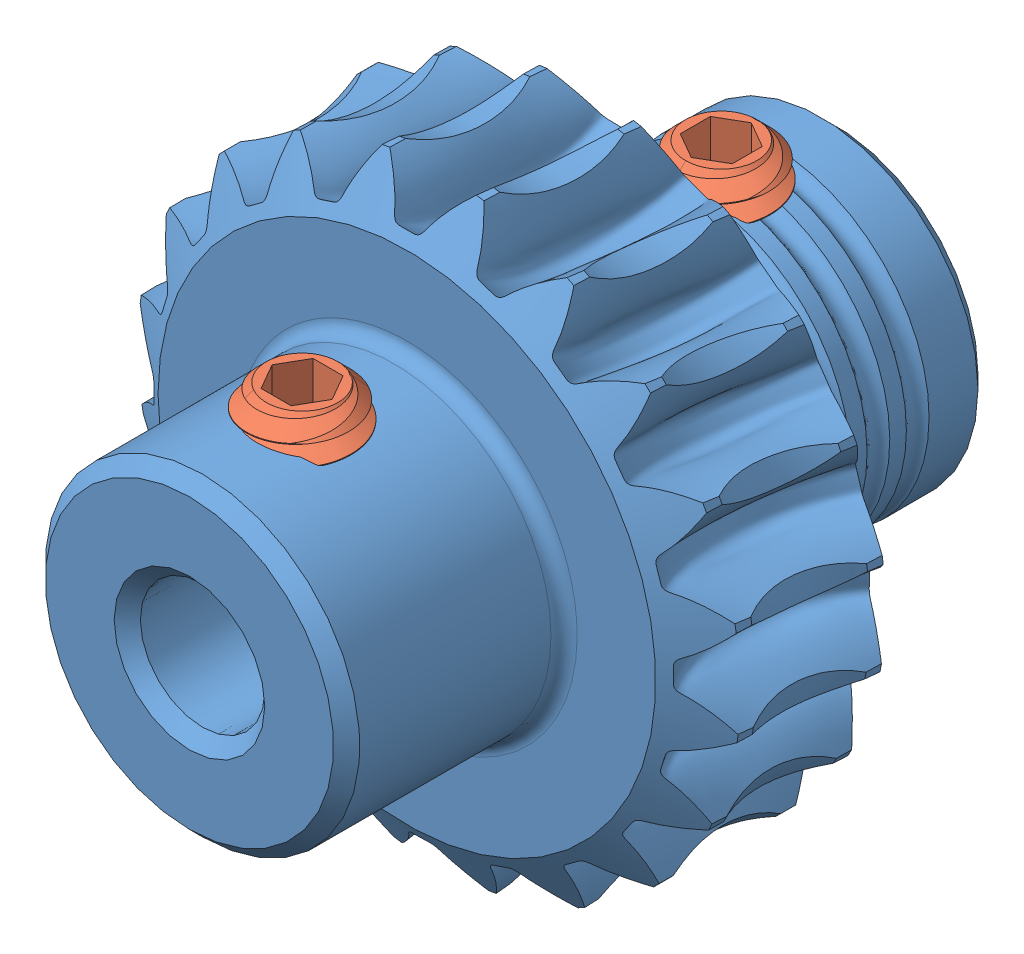
SolidWorks assembly Tetrix Worm Gear (20 to 1), configuration Default. Lengths in mm.
Overall size (23.76 23.76 24.6).
3 component instances, 2 part files, 0 mates.
Components (placement in the parent):
- Tetrix Worm Gear (20 to 1) Body-1: Tetrix Worm Gear (20 to 1) Body [Default] at origin size (23.76 23.76 24.6)
- Tetrix Worm Gear (20 to 1) Set Screw-1: Tetrix Worm Gear (20 to 1) Set Screw [Default] at (0 2.375 -8) size (4.02 4.91 3.99)
- Tetrix Worm Gear (20 to 1) Set Screw-2: Tetrix Worm Gear (20 to 1) Set Screw [Default] at (0 2.375 8) x (0.866025 0 0.5) z (-0.5 0 0.866025) size (4.02 4.91 3.99)
